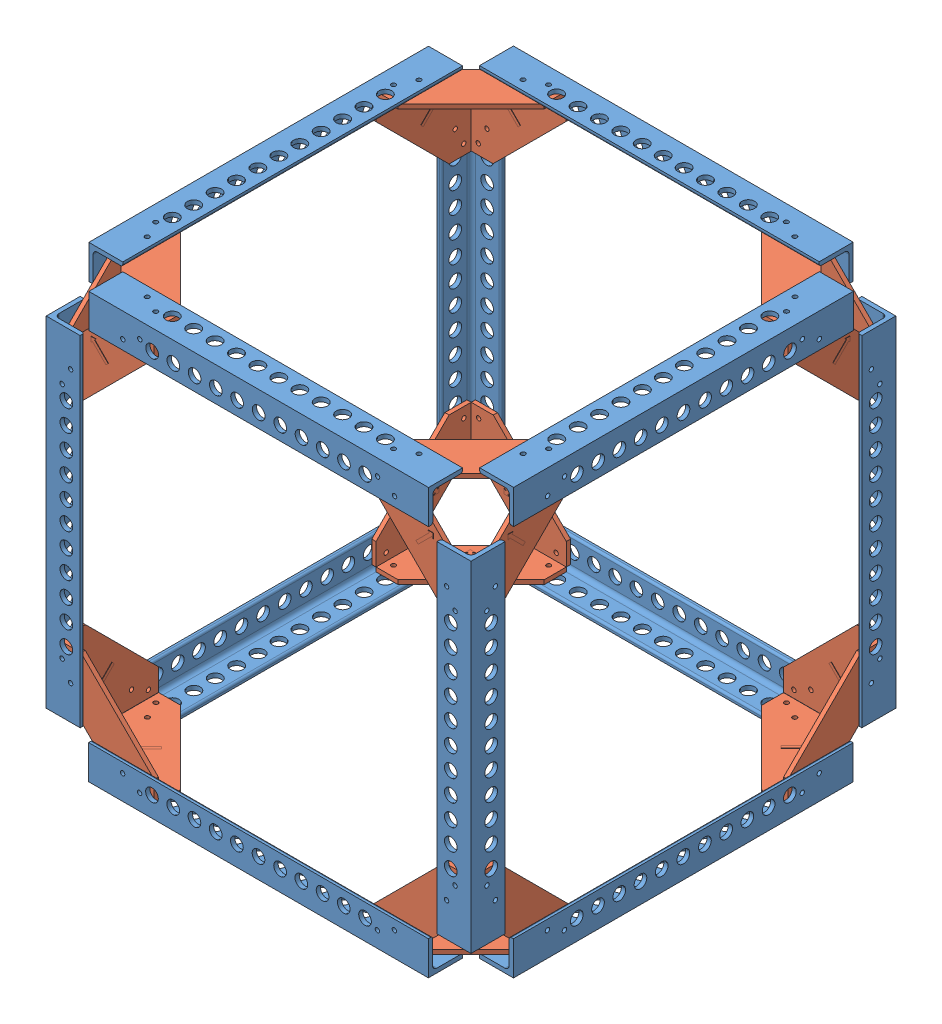
SolidWorks assembly test ass 2, configuration Default. Lengths in mm.
Overall size (317.63 317.62 317.63).
38 component instances, 2 part files, 46 mates.
Components (placement in the parent):
- test assemby 1-1: test assemby 1 [Default] at (189.8318 11.2658 54.9643) size (317.51 25.4 317.63)
  - MOD Al L rod-4: MOD Al L rod [8982K401] at (158.011 130.5289 151.3983) size (25.4 25.4 254)
  - MOD Al L rod-5: MOD Al L rod [8982K401] at (11.9531 130.5289 5.2213) x (0 0 -1) z (1 0 0) size (25.4 25.4 254)
  - draft bracket-1: draft bracket [Default] at (164.361 121.0039 -1.0017) size (71.12 3.43 71.12)
  - MOD Al L rod-7: MOD Al L rod [8982K401] at (11.834 130.5289 297.4562) x (0 0 1) z (-1 0 0) size (25.4 25.4 254)
  - draft bracket-3: draft bracket [Default] at (164.234 121.0039 303.8062) x (0 0 1) z (-1 0 0) size (71.12 3.43 71.12)
  - MOD Al L rod-9: MOD Al L rod [8982K401] at (-134.0969 130.5289 151.2713) x (-1 0 0) z (0 0 -1) size (25.4 25.4 254)
  - draft bracket-6: draft bracket [Default] at (-140.4469 121.0039 -1.1287) x (0 0 -1) z (1 0 0) size (71.12 3.43 71.12)
  - draft bracket-7: draft bracket [Default] at (-140.4469 121.0039 303.6713) x (-1 0 0) z (0 0 -1) size (71.12 3.43 71.12)
- MOD Al L rod-1: MOD Al L rod [8982K401] at (55.6237 287.8447 352.4206) x (-1 0 0) z (0 -1 0) size (25.4 25.4 254)
- draft bracket-2: draft bracket [Default] at (49.2737 135.4447 361.9456) x (0 -1 0) z (1 0 0) size (71.12 3.43 71.12)
- draft bracket-3: draft bracket [Default] at (46.2099 135.5717 358.6357) x (0 0 1) z (0 1 0) size (71.12 3.43 71.12)
- draft bracket-4: draft bracket [Default] at (354.1928 135.4526 361.9456) x (1 0 0) z (0 1 0) size (71.12 3.43 71.12)
- draft bracket-5: draft bracket [Default] at (357.3678 135.4447 358.7706) x (0 -1 0) z (0 0 -1) size (71.12 3.43 71.12)
- MOD Al L rod-2: MOD Al L rod [8982K401] at (347.8428 287.8447 352.4206) x (0 0 1) z (0 -1 0) size (25.4 25.4 254)
- draft bracket-6: draft bracket [Default] at (49.3849 135.4447 50.6607) x (-1 0 0) z (0 1 0) size (71.12 3.43 71.12)
- draft bracket-7: draft bracket [Default] at (46.2099 135.4447 53.8357) x (0 -1 0) z (0 0 1) size (71.12 3.43 71.12)
- MOD Al L rod-3: MOD Al L rod [8982K401] at (55.7349 287.8447 60.1857) x (0 0 -1) z (0 -1 0) size (25.4 25.4 254)
- draft bracket-10: draft bracket [Default] at (357.3678 135.4447 53.8357) x (0 0 -1) z (0 1 0) size (71.12 3.43 71.12)
- draft bracket-11: draft bracket [Default] at (354.1928 135.4447 50.6607) x (0 -1 0) z (-1 0 0) size (71.12 3.43 71.12)
- MOD Al L rod-5: MOD Al L rod [8982K401] at (347.8428 287.8447 60.1857) x (1 0 0) z (0 -1 0) size (25.4 25.4 254)
- test assemby 1-2: test assemby 1 [Default] at (189.8397 564.5428 357.6419) x (1 0 0) z (0 0 -1) size (317.51 25.4 317.63)
  - MOD Al L rod-4: MOD Al L rod [8982K401] at (158.011 130.5289 151.3983) size (25.4 25.4 254)
  - MOD Al L rod-5: MOD Al L rod [8982K401] at (11.9531 130.5289 5.2213) x (0 0 -1) z (1 0 0) size (25.4 25.4 254)
  - draft bracket-1: draft bracket [Default] at (164.361 121.0039 -1.0017) size (71.12 3.43 71.12)
  - MOD Al L rod-7: MOD Al L rod [8982K401] at (11.834 130.5289 297.4562) x (0 0 1) z (-1 0 0) size (25.4 25.4 254)
  - draft bracket-3: draft bracket [Default] at (164.234 121.0039 303.8062) x (0 0 1) z (-1 0 0) size (71.12 3.43 71.12)
  - MOD Al L rod-9: MOD Al L rod [8982K401] at (-134.0969 130.5289 151.2713) x (-1 0 0) z (0 0 -1) size (25.4 25.4 254)
  - draft bracket-6: draft bracket [Default] at (-140.4469 121.0039 -1.1287) x (0 0 -1) z (1 0 0) size (71.12 3.43 71.12)
  - draft bracket-7: draft bracket [Default] at (-140.4469 121.0039 303.6713) x (-1 0 0) z (0 0 -1) size (71.12 3.43 71.12)
- draft bracket-13: draft bracket [Default] at (354.1928 440.2368 358.7706) x (1 0 0) z (0 -1 0) size (71.12 3.43 71.12)
- draft bracket-14: draft bracket [Default] at (354.1928 440.2526 358.6436) x (0 1 0) z (0 0 -1) size (71.12 3.43 71.12)
- draft bracket-15: draft bracket [Default] at (49.2737 440.2368 358.7706) x (0 0 1) z (0 -1 0) size (71.12 3.43 71.12)
- draft bracket-16: draft bracket [Default] at (49.2737 440.3638 358.7706) x (0 1 0) z (1 0 0) size (71.12 3.43 71.12)
- draft bracket-17: draft bracket [Default] at (49.2816 440.3638 50.6607) x (0 1 0) z (1 0 0) size (71.12 3.43 71.12)
- draft bracket-18: draft bracket [Default] at (354.1928 440.3638 53.8357) x (0 1 0) z (-1 0 0) size (71.12 3.43 71.12)
- draft bracket-19: draft bracket [Default] at (46.2099 440.2447 53.8357) x (0 0 -1) z (0 -1 0) size (71.12 3.43 71.12)
- draft bracket-20: draft bracket [Default] at (354.1928 440.2368 53.8357) x (0 0 -1) z (0 -1 0) size (71.12 3.43 71.12)
Mates (geometry in assembly coordinates):
- Coincident1: coincident aligned: circle of test assemby 1-1/MOD Al L rod-7; circle of draft bracket-2
- Coincident3: coincident aligned: line of test assemby 1-1/MOD Al L rod-7 through (74.6658 135.4447 361.9456) axis (1 0 0); line of draft bracket-2 through (92.4537 135.4447 361.9456) axis (1 0 0)
- Coincident4: coincident anti-aligned: circle of MOD Al L rod-1; circle of draft bracket-2
- Coincident6: coincident aligned: line of MOD Al L rod-1 through (49.2737 160.8447 361.9456) axis (0 1 0); line of draft bracket-2 through (49.2737 178.6247 361.9456) axis (0 1 0)
- Coincident7: coincident aligned: circle of test assemby 1-1/MOD Al L rod-9; circle of draft bracket-3
- Parallel1: parallel aligned: line of MOD Al L rod-1 through (46.0987 160.8447 358.7706) axis (0 1 0); line of draft bracket-3 through (46.2099 178.7517 358.6357) axis (0 1 0)
- Coincident13: coincident anti-aligned: circle of draft bracket-5; circle of MOD Al L rod-2
- Coincident14: coincident aligned: line of draft bracket-5 through (357.3678 178.6247 358.7706) axis (0 1 0); line of MOD Al L rod-2 through (357.3678 160.8447 358.7706) axis (0 1 0)
- Parallel2: parallel aligned: line of draft bracket-4 through (354.1928 178.6326 361.9456) axis (0 1 0); line of MOD Al L rod-2 through (354.1928 160.8447 361.9456) axis (0 1 0)
- Coincident15: coincident aligned: circle of draft bracket-4; circle of MOD Al L rod-2
- Coincident16: coincident aligned: line of test assemby 1-1/MOD Al L rod-4 through (357.3678 135.4447 333.3627) axis (0 0 -1); line of draft bracket-5 through (357.3678 135.4447 315.5906) axis (0 0 -1)
- Coincident17: coincident: circle of test assemby 1-1/MOD Al L rod-7; circle of draft bracket-4
- Parallel4: parallel anti-aligned: line of test assemby 1-1/MOD Al L rod-7 through (74.6658 135.4447 361.9456) axis (1 0 0); line of draft bracket-4 through (311.0128 135.4526 361.9456) axis (-1 0 0)
- Coincident19: coincident anti-aligned: circle of draft bracket-7; circle of MOD Al L rod-3
- Coincident20: coincident aligned: line of draft bracket-7 through (46.2099 178.6247 53.8357) axis (0 1 0); line of MOD Al L rod-3 through (46.2099 160.8447 53.8357) axis (0 1 0)
- Coincident21: coincident aligned: line of draft bracket-6 through (49.3849 178.6247 50.6607) axis (0 1 0); line of MOD Al L rod-3 through (49.3849 160.8447 50.6607) axis (0 1 0)
- Coincident23: coincident aligned: circle of draft bracket-6; circle of MOD Al L rod-3
- Coincident32: coincident anti-aligned: line of test assemby 1-1/MOD Al L rod-5 through (328.7849 135.4447 50.6607) axis (-1 0 0); line of draft bracket-6 through (92.5649 135.4447 50.6607) axis (1 0 0)
- Coincident33: coincident aligned: circle of test assemby 1-1/MOD Al L rod-9; circle of draft bracket-7
- Coincident34: coincident anti-aligned: circle of draft bracket-9; circle of MOD Al L rod-4
- Coincident35: coincident aligned: line of draft bracket-9 through (1439.6661 1201.1399 56.0831) axis (0 1 0); line of MOD Al L rod-4 through (1439.6661 1183.3599 56.0831) axis (0 1 0)
- Coincident36: coincident aligned: line of draft bracket-11 through (354.1928 178.6247 50.6607) axis (0 1 0); line of MOD Al L rod-5 through (354.1928 160.8447 50.6607) axis (0 1 0)
- Coincident37: coincident anti-aligned: circle of draft bracket-11; circle of MOD Al L rod-5
- Coincident38: coincident aligned: circle of draft bracket-10; circle of MOD Al L rod-5
- Coincident39: coincident aligned: line of draft bracket-10 through (357.3678 178.6247 53.8357) axis (0 1 0); line of MOD Al L rod-5 through (357.3678 160.8447 53.8357) axis (0 1 0)
- Coincident40: coincident anti-aligned: line of test assemby 1-1/MOD Al L rod-4 through (357.3678 135.4447 333.3627) axis (0 0 -1); line of draft bracket-10 through (357.3678 135.4447 97.0157) axis (0 0 1)
- Coincident41: coincident aligned: line of test assemby 1-1/MOD Al L rod-5 through (328.7849 135.4447 50.6607) axis (-1 0 0); line of draft bracket-11 through (311.0128 135.4447 50.6607) axis (-1 0 0)
- Coincident44: coincident anti-aligned: circle of MOD Al L rod-2; circle of draft bracket-13
- Coincident45: coincident anti-aligned: circle of test assemby 1-2/MOD Al L rod-5; circle of draft bracket-13
- Coincident46: coincident anti-aligned: line of MOD Al L rod-2 through (354.1928 160.8447 361.9456) axis (0 1 0); line of draft bracket-13 through (354.1928 397.0568 361.9456) axis (0 -1 0)
- Parallel5: parallel aligned: line of test assemby 1-2/MOD Al L rod-5 through (328.7928 440.3638 361.9456) axis (-1 0 0); line of draft bracket-13 through (311.0128 440.2368 361.9456) axis (-1 0 0)
- Coincident47: coincident anti-aligned: circle of MOD Al L rod-2; circle of draft bracket-14
- Parallel6: parallel anti-aligned: line of test assemby 1-2/MOD Al L rod-4 through (357.3757 440.3638 79.2436) axis (0 0 1); line of draft bracket-14 through (357.3678 440.2526 315.4636) axis (0 0 -1)
- Coincident52: coincident anti-aligned: line of test assemby 1-2/MOD Al L rod-5 through (328.7928 440.3638 361.9456) axis (-1 0 0); line of draft bracket-16 through (92.4537 440.3638 361.9456) axis (1 0 0)
- Coincident53: coincident anti-aligned: line of MOD Al L rod-1 through (49.2737 160.8447 361.9456) axis (0 1 0); line of draft bracket-16 through (49.2737 397.1838 361.9456) axis (0 -1 0)
- Coincident59: coincident aligned: line of test assemby 1-2/MOD Al L rod-9 through (46.2178 440.3638 333.3706) axis (0 0 -1); line of draft bracket-15 through (46.0987 440.2368 315.5906) axis (0 0 -1)
- Coincident62: coincident anti-aligned: circle of MOD Al L rod-1; circle of draft bracket-15
- Parallel12: parallel aligned: line of test assemby 1-2/MOD Al L rod-9 through (46.2178 440.3638 333.3706) axis (0 0 -1); line of draft bracket-15 through (46.0987 440.2368 315.5906) axis (0 0 -1)
- Coincident67: coincident aligned: circle of test assemby 1-2/MOD Al L rod-7; circle of draft bracket-17
- Parallel13: parallel anti-aligned: line of MOD Al L rod-3 through (49.3849 160.8447 50.6607) axis (0 1 0); line of draft bracket-17 through (49.2816 397.1838 50.6607) axis (0 -1 0)
- Coincident73: coincident anti-aligned: line of test assemby 1-2/MOD Al L rod-7 through (74.6737 440.3638 50.6607) axis (1 0 0); line of draft bracket-18 through (311.0128 440.3638 50.6607) axis (-1 0 0)
- Coincident74: coincident anti-aligned: line of MOD Al L rod-5 through (354.1928 160.8447 50.6607) axis (0 1 0); line of draft bracket-18 through (354.1928 397.1838 50.6607) axis (0 -1 0)
- Coincident79: coincident aligned: circle of MOD Al L rod-3; circle of draft bracket-19
- Parallel15: parallel anti-aligned: line of test assemby 1-2/MOD Al L rod-9 through (46.2178 440.3638 333.3706) axis (0 0 -1); line of draft bracket-19 through (46.2099 440.2447 97.0157) axis (0 0 1)
- Coincident83: coincident anti-aligned: circle of MOD Al L rod-5; circle of draft bracket-20
- Parallel16: parallel aligned: line of test assemby 1-2/MOD Al L rod-4 through (357.3757 440.3638 79.2436) axis (0 0 1); line of draft bracket-20 through (357.3678 440.2368 97.0157) axis (0 0 1)
